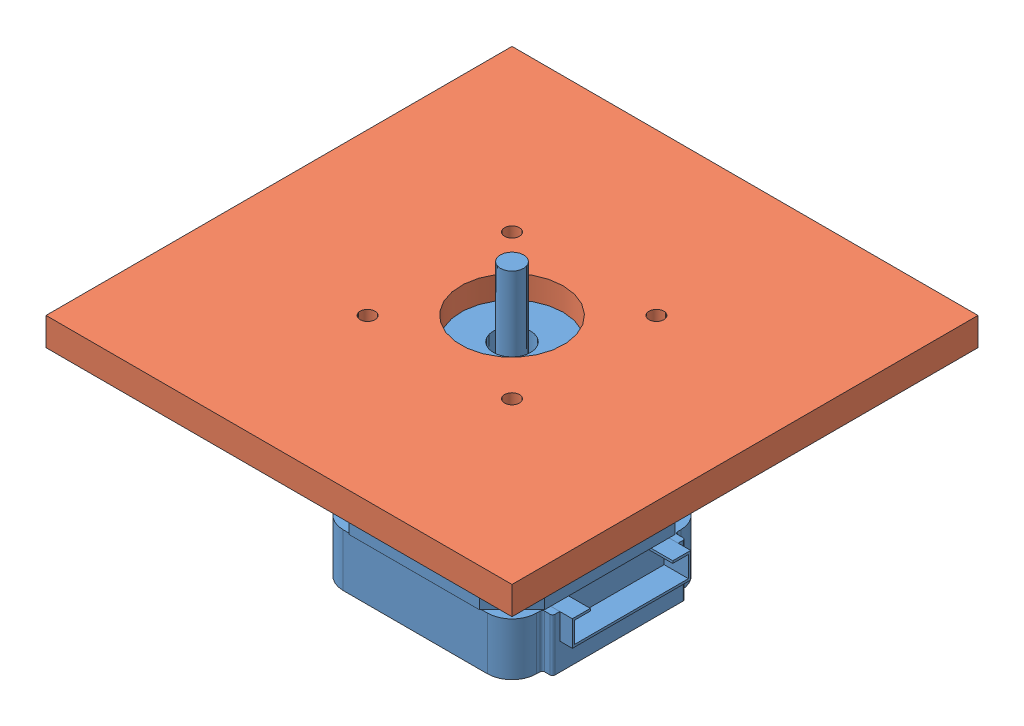
SolidWorks assembly zzz_nema 17 features, configuration Default. Lengths in mm.
Overall size (100 58.5 100).
2 component instances, 2 part files, 4 mates.
Components (placement in the parent):
- x_nema 17-1: x_nema 17 [Default] at origin size (46.65 58.5 42)
- plank^zzz_nema 17 features-1: plank^zzz_nema 17 features [Default] at (0 42.5 0) size (100 6 100) (virtual)
Mates (geometry in assembly coordinates):
- Coincident1: coordinate: point of x_nema 17-1; point of assembly
- Coincident2: coincident anti-aligned: plane of x_nema 17-1 through (0 42.5 0) normal (0 1 0); plane of plank^zzz_nema 17 features-1 through (0 42.5 0) normal (0 -1 0)
- Coincident3: coincident aligned: plane of plank^zzz_nema 17 features-1 through (0 42.5 0) normal (1 0 0); plane of assembly through (0 0 0) normal (1 0 0)
- Coincident4: coincident aligned: plane of plank^zzz_nema 17 features-1 through (0 42.5 0) normal (0 0 1); plane of assembly through (0 0 0) normal (0 0 1)
